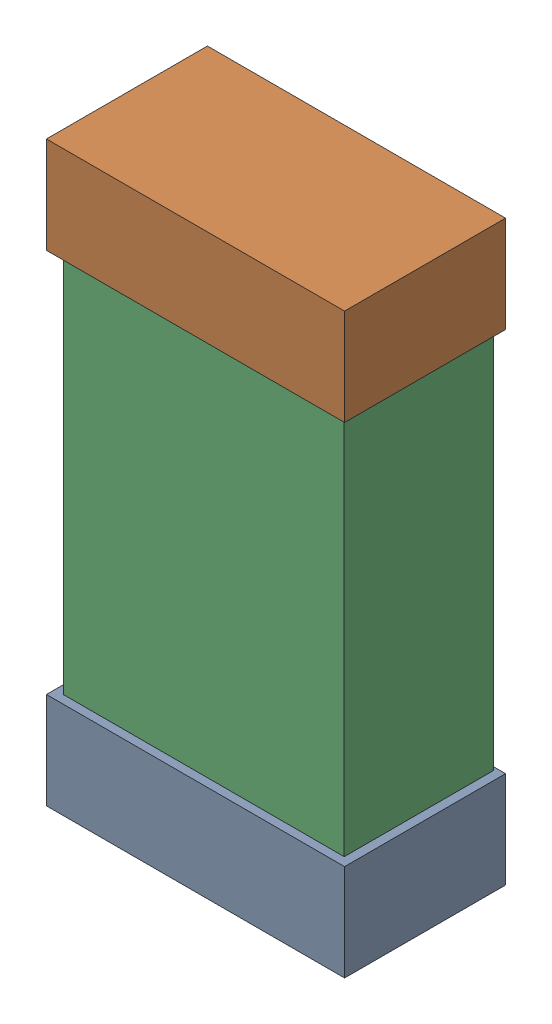
SolidWorks assembly R24, configuration Default. Lengths in mm.
Overall size (0.85 1.65 0.46).
6 component instances, 2 part files, 0 mates.
Components (placement in the parent):
- 432138512_108-1: 432138512_108 [Default] at (18.8149 18.7674 -0.8715) size (0.85 0.28 0.46)
  - Extruded-1: Extruded [Default] at origin size (0.85 0.28 0.46)
- 432138512_109-1: 432138512_109 [Default] at (18.8149 20.1389 -0.8715) size (0.85 0.28 0.46)
  - Extruded-1: Extruded [Default] at origin size (0.85 0.28 0.46)
- 432124816_54-1: 432124816_54 [Default] at (18.8149 19.4531 -0.8615) size (0.8 1.5 0.42)
  - Extruded (1)-1: Extruded (1) [Default] at origin size (0.8 1.5 0.42)
